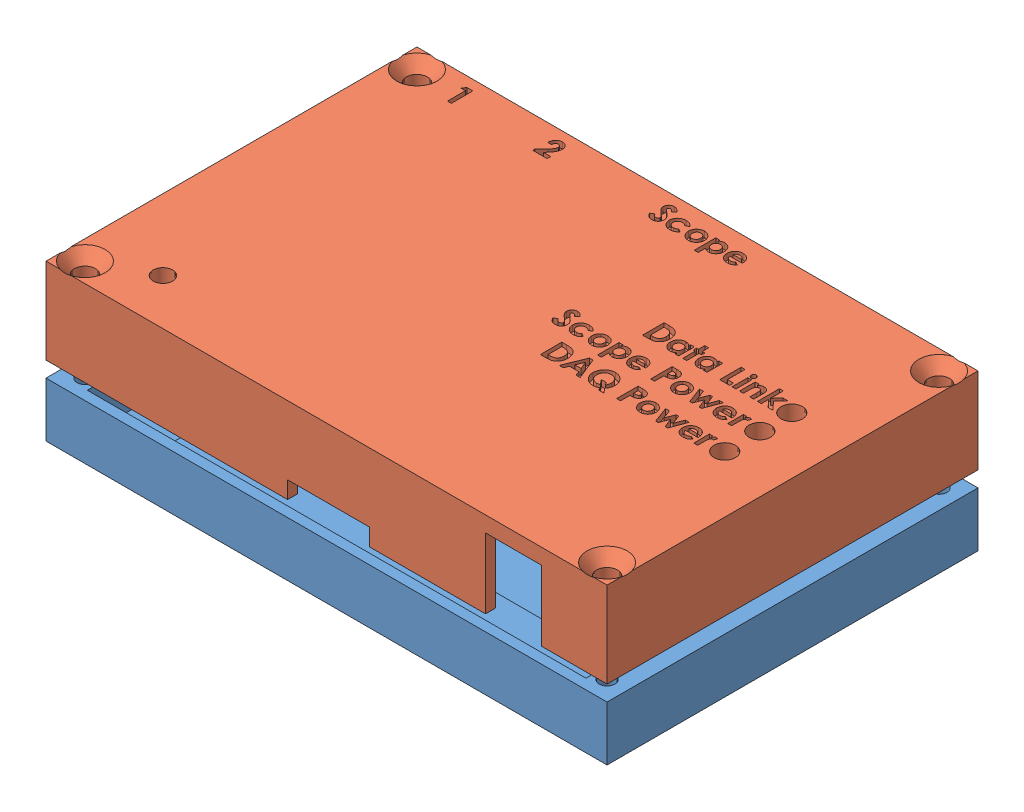
SolidWorks assembly DAQ Boxv3.2, configuration Default. Lengths in mm.
Overall size (91.44 25.59 60.45).
2 component instances, 2 part files, 3 mates.
Components (placement in the parent):
- Bottom-1: Bottom [Default] at (-11.2026 -6.463 7.2824) size (91.44 8.89 60.45)
- Top-1: Top [Default] at (-11.2026 4.967 7.2824) size (91.44 14.16 60.45)
Mates (geometry in assembly coordinates):
- Concentric1: concentric anti-aligned: cylinder of Bottom-1 through (-53.7476 -6.463 34.3334) axis (0 1 0) radius 1.2891; cylinder of Top-1 through (-53.7476 18.937 34.3334) axis (0 -1 0) radius 1.7145
- Concentric2: concentric anti-aligned: cylinder of Bottom-1 through (-53.7476 -6.463 -19.7686) axis (0 1 0) radius 1.2891; cylinder of Top-1 through (-53.7476 18.937 -19.7686) axis (0 -1 0) radius 1.7145
- Distance1: distance = 2.54 mm anti-aligned: plane of Bottom-1 through (-11.2026 2.427 7.2824) normal (0 1 0); plane of Top-1 through (-11.2026 4.967 7.2824) normal (0 -1 0)
